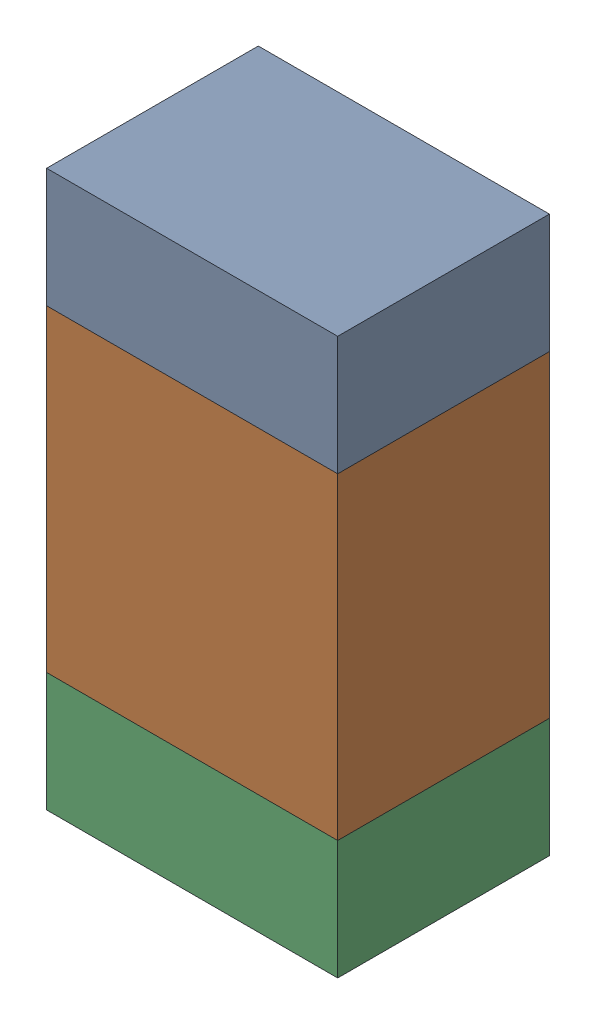
SolidWorks assembly R204PCB, configuration Default. Lengths in mm.
Overall size (0.55 1.05 0.4).
6 component instances, 2 part files, 0 mates.
Components (placement in the parent):
- 846483288-1: 846483288 [Default] at (89.1001 125.2124 0) size (0.55 0.22 0.4)
  - Extruded_12-1: Extruded_12 [Default] at origin size (0.55 0.22 0.4)
- 846483424-1: 846483424 [Default] at (89.1001 124.7999 0) size (0.55 0.6 0.4)
  - Extruded_13-1: Extruded_13 [Default] at origin size (0.55 0.6 0.4)
- 846483288-2: 846483288 [Default] at (89.1001 124.3874 0) size (0.55 0.22 0.4)
  - Extruded_12-1: Extruded_12 [Default] at origin size (0.55 0.22 0.4)
